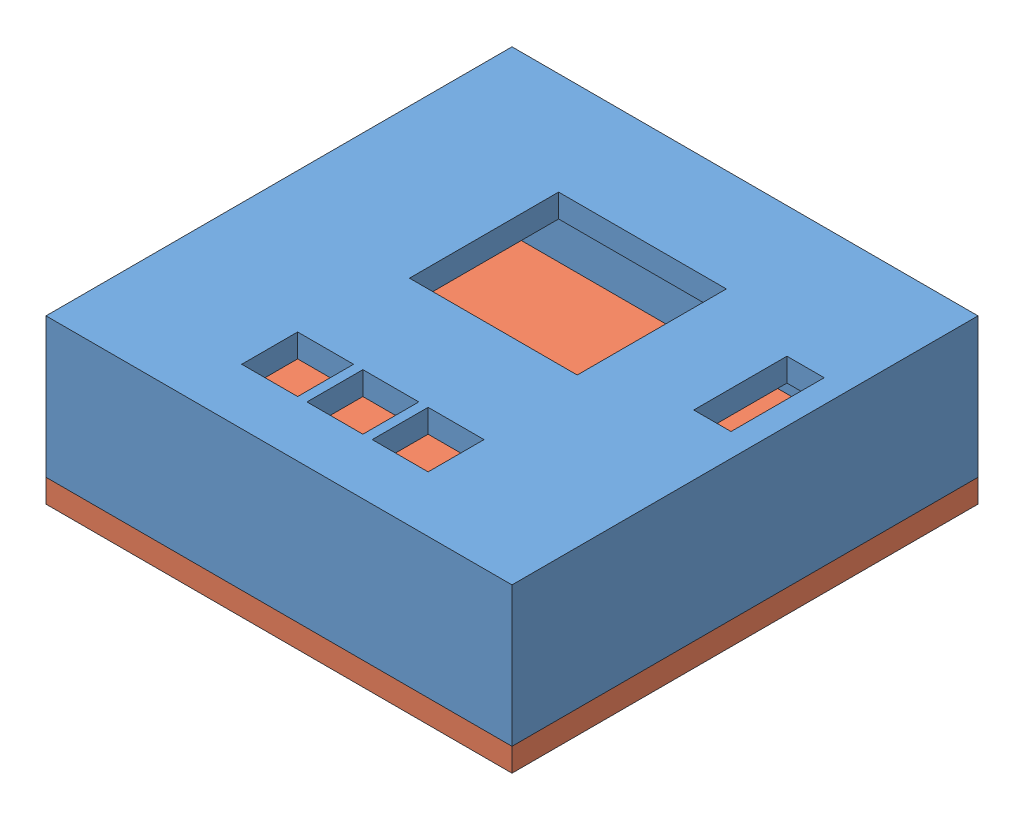
SolidWorks assembly Assem1, configuration Default. Lengths in mm.
Overall size (100 35 100).
2 component instances, 2 part files, 2 mates.
Components (placement in the parent):
- Part1-1: Part1 [Default] at (36.9351 24.0781 82.4736) size (100 30 100)
- Part2-1: Part2 [Default] at (36.9351 24.0781 82.4736) size (100 5 100)
Mates (geometry in assembly coordinates):
- Coincident1: coincident: plane of Part1-1 through (36.9351 29.0781 82.4736) normal (0 -1 0); plane of Part2-1 through (36.9351 29.0781 82.4736) normal (0 1 0)
- Concentric1: concentric anti-aligned: cylinder of Part1-1 through (-10.5649 29.0781 36.4736) axis (0 -1 0) radius 2; cylinder of Part2-1 through (-10.5649 29.0781 36.4736) axis (0 1 0) radius 2
